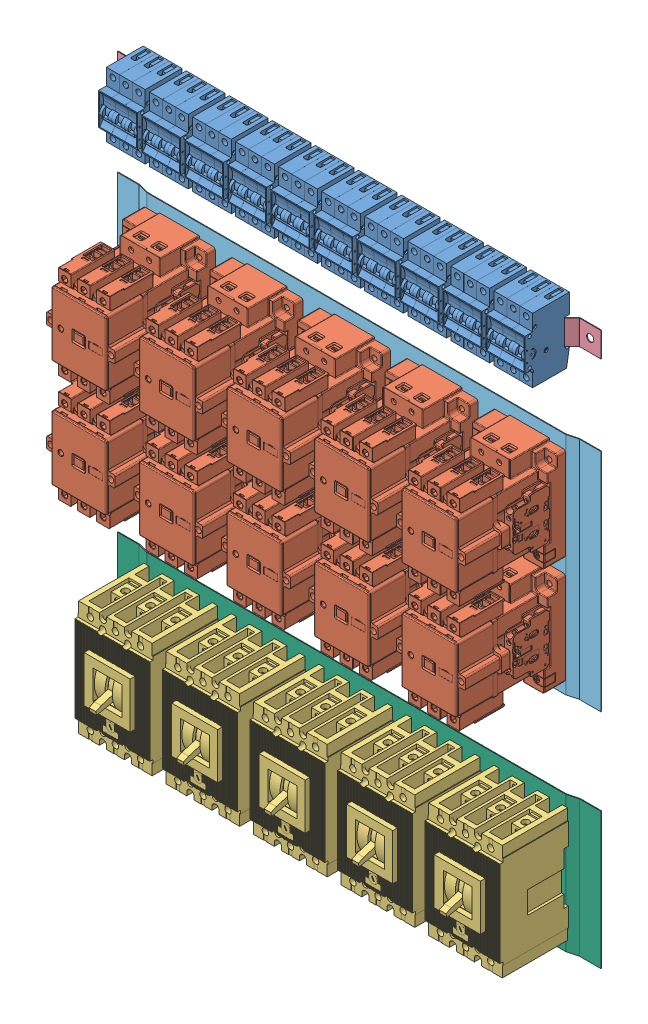
SolidWorks assembly tripper, configuration Default. Lengths in mm.
Overall size (674.02 798.75 145.25).
28 component instances, 6 part files, 22 mates.
Components (placement in the parent):
- User Library-5SX3P-1: User Library-5SX3P [Default] at (-35.7592 -68.0424 0) x (1 0 0) z (0 -1 0) size (54.02 62 90)
- User Library-5SX3P-2: User Library-5SX3P [Default] at (24.2408 -68.0424 0) x (1 0 0) z (0 -1 0) size (54.02 62 90)
- User Library-5SX3P-3: User Library-5SX3P [Default] at (84.2408 -68.0424 0) x (1 0 0) z (0 -1 0) size (54.02 62 90)
- User Library-5SX3P-4: User Library-5SX3P [Default] at (144.2408 -68.0424 0) x (1 0 0) z (0 -1 0) size (54.02 62 90)
- User Library-5SX3P-5: User Library-5SX3P [Default] at (204.2408 -68.0424 0) x (1 0 0) z (0 -1 0) size (54.02 62 90)
- User Library-5SX3P-6: User Library-5SX3P [Default] at (264.2408 -68.0424 0) x (1 0 0) z (0 -1 0) size (54.02 62 90)
- User Library-5SX3P-7: User Library-5SX3P [Default] at (324.2408 -68.0424 0) x (1 0 0) z (0 -1 0) size (54.02 62 90)
- User Library-5SX3P-8: User Library-5SX3P [Default] at (384.2408 -68.0424 0) x (1 0 0) z (0 -1 0) size (54.02 62 90)
- User Library-5SX3P-9: User Library-5SX3P [Default] at (444.2408 -68.0424 0) x (1 0 0) z (0 -1 0) size (54.02 62 90)
- User Library-5SX3P-10: User Library-5SX3P [Default] at (504.2408 -68.0424 0) x (1 0 0) z (0 -1 0) size (54.02 62 90)
- User Library-3TF48-1: User Library-3TF48 [Default] at (-12.5092 -281.5471 0) size (101.5 134.25 140.25)
- User Library-3TF48-11: User Library-3TF48 [Default] at (109.4908 -281.5471 0) size (101.5 134.25 140.25)
- User Library-3TF48-12: User Library-3TF48 [Default] at (231.4908 -281.5471 0) size (101.5 134.25 140.25)
- User Library-3TF48-13: User Library-3TF48 [Default] at (353.4908 -281.5471 0) size (101.5 134.25 140.25)
- User Library-3TF48-14: User Library-3TF48 [Default] at (475.4908 -281.5471 0) size (101.5 134.25 140.25)
- User Library-3TF48-15: User Library-3TF48 [Default] at (-12.5092 -431.5471 0) size (101.5 134.25 140.25)
- User Library-3TF48-16: User Library-3TF48 [Default] at (109.4908 -431.5471 0) size (101.5 134.25 140.25)
- User Library-3TF48-17: User Library-3TF48 [Default] at (231.4908 -431.5471 0) size (101.5 134.25 140.25)
- User Library-3TF48-18: User Library-3TF48 [Default] at (353.4908 -431.5471 0) size (101.5 134.25 140.25)
- User Library-3TF48-19: User Library-3TF48 [Default] at (475.4908 -431.5471 0) size (101.5 134.25 140.25)
- User Library-3VE5-2: User Library-3VE5 [Default] at (-10.5092 -726.7971 0) size (104.5 160 122.96)
- Part5^tripper-1: Part5^tripper [Default] at (531.2608 -68.0424 0) x (0 1 0) z (1 0 0) size (30 12 674.02) (virtual)
- Part6^tripper-1: Part6^tripper [Default] at (475.4908 -281.5471 0) x (-1 0 0) z (0 0 -1) size (674.02 314.25 5) (virtual)
- Part7^tripper-1: Part7^tripper [Default] at (-10.5092 -726.7971 0) x (-1 0 0) z (0 0 -1) size (674.02 190 5) (virtual)
- User Library-3VE5-4: User Library-3VE5 [Default] at (111.4908 -726.7971 0) size (104.5 160 122.96)
- User Library-3VE5-5: User Library-3VE5 [Default] at (233.4908 -726.7971 0) size (104.5 160 122.96)
- User Library-3VE5-6: User Library-3VE5 [Default] at (355.4908 -726.7971 0) size (104.5 160 122.96)
- User Library-3VE5-7: User Library-3VE5 [Default] at (477.4908 -726.7971 0) size (104.5 160 122.96)
Mates (geometry in assembly coordinates):
- Coincident1: coincident anti-aligned: plane of User Library-5SX3P-1 through (-181.1021 -23.0471 0) normal (0 0 -1); plane of assembly through (0 0 0) normal (0 0 1)
- Coincident2: coincident aligned: plane of User Library-5SX3P-1 through (-181.1021 -23.0471 0) normal (0 0 -1); plane of User Library-3TF48-1 through (37.7408 -346.7971 0) normal (0 0 -1)
- Coincident3: coincident aligned: plane of User Library-5SX3P-1 through (-62.7592 -45.5471 -7.4405) normal (-1 0 0); plane of User Library-3TF48-1 through (-62.7592 -216.2971 25.25) normal (-1 0 0)
- Distance1: distance = 100 mm anti-aligned: plane of User Library-5SX3P-1 through (-44.7592 -113.0471 3.9998) normal (0 -1 0); plane of User Library-3TF48-1 through (-40.5092 -213.0471 25.25) normal (0 1 0)
- Coincident5: coincident aligned: plane of User Library-3TF48-15 through (37.7408 -496.7971 0) normal (0 0 -1); plane of User Library-3VE5-2 through (-62.7592 -806.7971 0) normal (0 0 -1)
- Coincident9: coincident aligned: plane of User Library-3TF48-15 through (-62.7592 -366.2971 25.25) normal (-1 0 0); plane of User Library-3VE5-2 through (-62.7592 -646.7971 95) normal (-1 0 0)
- Coincident10: coincident aligned: plane of User Library-5SX3P-1 through (-62.7592 -45.5471 -7.4405) normal (-1 0 0); plane of User Library-3TF48-1 through (-62.7592 -216.2971 25.25) normal (-1 0 0)
- Distance3: distance = 150 mm anti-aligned: plane of User Library-3TF48-15 through (-62.7592 -496.7971 25.25) normal (0 -1 0); plane of User Library-3VE5-2 through (-62.7592 -646.7971 95) normal (0 1 0)
- InPlace1: in place: plane of User Library-5SX3P-10 through (531.2608 -45.5471 -7.4405) normal (1 0 0); plane of ? through (531.2608 0 0) normal (1 0 0); moOrthogonalPlaneRef_w of User Library-5SX3P-10 through (531.2608 -45.5471 -7.4405) normal (1 0 0); unknown of ?; plane of User Library-5SX3P-10 through (531.2608 -45.5471 -7.4405) normal (1 0 0); unknown of ?; plane of User Library-5SX3P-10 through (531.2608 -45.5471 -7.4405) normal (1 0 0); unknown of Part5^tripper-1
- Coincident12: coincident aligned: plane of User Library-5SX3P-10; plane of Part5^tripper-1
- Coincident13: coincident aligned: moOrthogonalPlaneRef_w of User Library-5SX3P-10 through (531.2608 -68.0424 0) normal (0 0 1); plane of Part5^tripper-1
- Coincident14: coincident anti-aligned: moOrthogonalPlaneRef_w of User Library-5SX3P-10 through (531.2608 -68.0424 0) normal (0 -1 0); plane of Part5^tripper-1
- InPlace2: in place: plane of ? through (525.7408 -396.7971 0) normal (0 0 -1); plane of ? through (0 0 0) normal (0 0 -1); plane of ? through (525.7408 -396.7971 0) normal (0 0 -1); line of ? through (-55 0 0) axis (0 0 1); plane of ? through (525.7408 -396.7971 0) normal (0 0 -1); plane of ? through (0 0 0) normal (-1 0 0); plane of User Library-3TF48-14 through (525.7408 -346.7971 0) normal (0 0 -1); unknown of Part6^tripper-1
- Coincident15: coincident aligned: plane of User Library-3TF48-14; plane of Part6^tripper-1
- Coincident16: coincident aligned: moOrthogonalPlaneRef_w of User Library-3TF48-14 through (475.4908 -281.5471 0) normal (0 1 0); plane of Part6^tripper-1
- Coincident17: coincident anti-aligned: moOrthogonalPlaneRef_w of User Library-3TF48-14 through (475.4908 -281.5471 0) normal (1 0 0); plane of Part6^tripper-1 through (475.4908 -281.5471 0) normal (-1 0 0)
- InPlace3: in place: plane of ? through (-62.7592 -856.7971 0) normal (0 0 -1); plane of ? through (0 0 0) normal (0 0 -1); plane of ? through (-62.7592 -856.7971 0) normal (0 0 -1); line of ? through (-55 0 0) axis (0 0 1); plane of ? through (-62.7592 -856.7971 0) normal (0 0 -1); plane of ? through (0 0 0) normal (-1 0 0); plane of User Library-3VE5-2 through (-62.7592 -806.7971 0) normal (0 0 -1); unknown of Part7^tripper-1
- Coincident18: coincident aligned: plane of User Library-3VE5-2; plane of Part7^tripper-1
- Coincident19: coincident aligned: moOrthogonalPlaneRef_w of User Library-3VE5-2 through (-10.5092 -726.7971 0) normal (0 1 0); plane of Part7^tripper-1
- Coincident20: coincident anti-aligned: plane of User Library-3VE5-2 through (-10.5092 -726.7971 0) normal (1 0 0); plane of Part7^tripper-1 through (-10.5092 -726.7971 0) normal (-1 0 0)
- LocalLPattern2: unknown: line of User Library-3TF48-1 through (23.4908 -238.0471 140.25) axis (-1 0 0); line of User Library-3TF48-1 through (-49.2592 -238.7971 140.25) axis (0 -1 0); unknown of User Library-5SX3P-10; unknown of User Library-5SX3P-10; unknown of User Library-5SX3P-1; unknown of Part5^tripper-1; unknown of Part5^tripper-1; unknown of Part5^tripper-1; unknown of Part5^tripper-1; unknown of Part6^tripper-1; unknown of Part6^tripper-1; unknown of Part6^tripper-1; unknown of Part6^tripper-1
- LocalLPattern3: unknown: line of Part7^tripper-1 through (-59.6942 -631.7971 0) axis (1 0 0)
